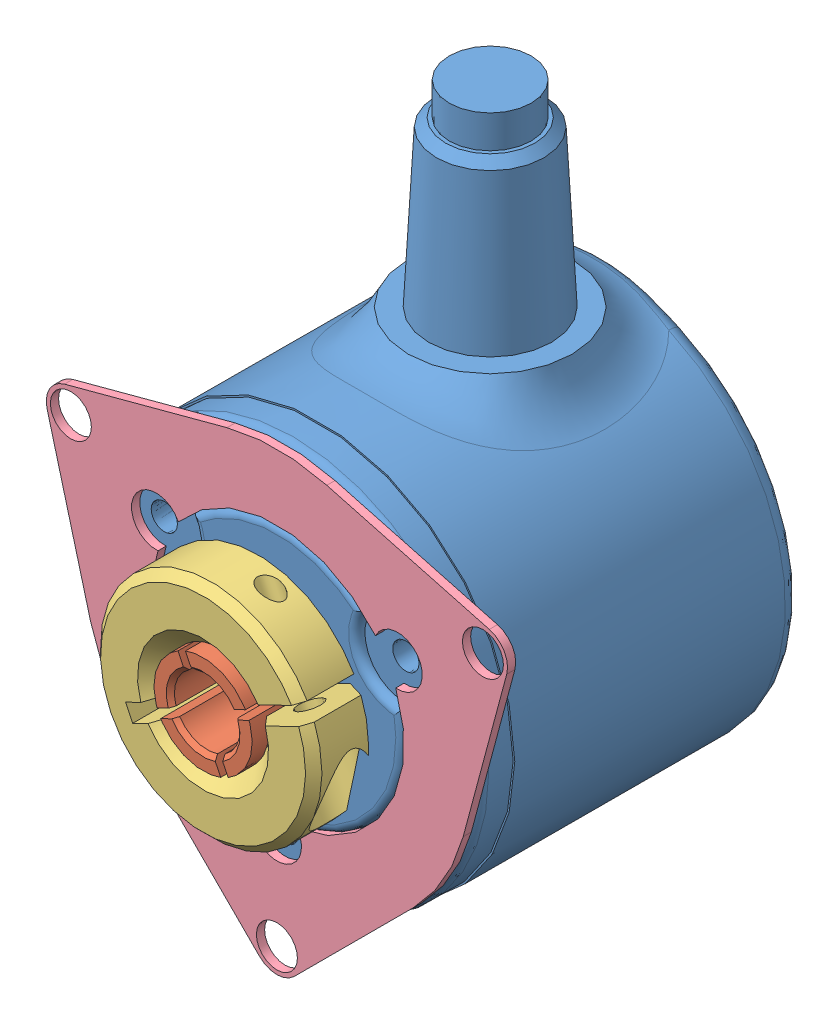
SolidWorks assembly Codeur_2MRH, configuration Default. Lengths in mm.
Overall size (38.09 42.8 24.5).
8 component instances, 6 part files, 16 mates.
Components (placement in the parent):
- corps_codeur_2MRH-1: corps_codeur_2MRH [Default] at (3.2886 -2.5929 -14.3048) size (24 36.75 20.04)
- mandrin_codeur_2MRH-1: mandrin_codeur_2MRH [Default] at (3.2886 -2.5929 -3.8048) x (-0.434638 0.900605 0) z (0 0 1) size (6 6 14)
- bague_codeur_2MRH-1: bague_codeur_2MRH [Default] at (3.2886 -2.5929 5.6952) x (0.434638 -0.900605 0) z (0 0 1) size (13.5 13.48 4.5)
- Socket Head Cap Screw_AM-2: Socket Head Cap Screw_AM [B18.3.1M - 1.6 x 0.35 x 5 Hex SHCS -- 5NHX] at (9.1066 -4.3376 7.9452) x (-0.434638 0.900605 0) z (0 0 1) (suppressed, hidden)
- Pan Slot Head_AM-4: Pan Slot Head_AM [B18.6.7M - M2 x 0.4 x 4 Slotted PHMS --4N] at (10.6498 1.6571 7.2952) x (0 0 -1) z (0.728333 -0.685223 0) (suppressed, hidden)
- Pan Slot Head_AM-5: Pan Slot Head_AM [B18.6.7M - M2 x 0.4 x 4 Slotted PHMS --4N] at (-4.0726 1.6571 7.2952) x (0 0 -1) z (0.998972 -0.045336 0) (suppressed, hidden)
- Pan Slot Head_AM-6: Pan Slot Head_AM [B18.6.7M - M2 x 0.4 x 4 Slotted PHMS --4N] at (3.2886 -11.0929 7.2952) x (0 0 -1) z (-0.043781 0.999041 0) (suppressed, hidden)
- Bride_membrane-1: Bride_membrane [Default] at (3.2886 -2.5929 5.6952) x (0.5 0.866025 0) z (-0.866025 0.5 0) size (28.11 0.5 27.75)
Mates (geometry in assembly coordinates):
- Coaxiale2: concentric anti-aligned: cylinder of corps_codeur_2MRH-1 through (3.2886 -2.5929 -3.8048) axis (0 0 1) radius 3; cylinder of mandrin_codeur_2MRH-1 through (3.2886 -2.5929 10.1952) axis (0 0 -1) radius 3
- Coïncidente1: coincident anti-aligned: plane of corps_codeur_2MRH-1 through (3.2886 -2.5929 -3.8048) normal (0 0 1); plane of mandrin_codeur_2MRH-1 through (3.2886 -2.5929 -3.8048) normal (0 0 -1)
- Coïncidente2: coincident anti-aligned: plane of corps_codeur_2MRH-1 through (3.2886 -2.5929 5.6952) normal (0 0 1); plane of bague_codeur_2MRH-1 through (3.2886 -2.5929 5.6952) normal (0 0 -1)
- Coaxiale3: concentric aligned: cylinder of mandrin_codeur_2MRH-1 through (3.2886 -2.5929 10.1952) axis (0 0 -1) radius 3; cylinder of bague_codeur_2MRH-1 through (3.2886 -2.5929 10.1952) axis (0 0 -1) radius 3
- Parallèle1: parallel aligned: plane of mandrin_codeur_2MRH-1 through (3.4051 -2.2591 0.1952) normal (0.434638 -0.900605 0); plane of bague_codeur_2MRH-1 through (9.1337 0.7831 5.6942) normal (0.434638 -0.900605 0)
- Coaxiale41: concentric anti-aligned: cylinder of bague_codeur_2MRH-1 through (8.4112 -2.8966 7.9452) axis (-0.434638 0.900605 0) radius 0.75; cylinder of Socket Head Cap Screw_AM-2 through (22.9064 -32.9318 7.9452) axis (0.434638 -0.900605 0) radius 1.5
- Coïncidente41: coincident anti-aligned: plane of bague_codeur_2MRH-1 through (8.4112 -2.8966 7.9452) normal (0.434638 -0.900605 0); plane of Socket Head Cap Screw_AM-2 through (7.0603 -3.5486 7.9452) normal (-0.434638 0.900605 0)
- Coaxiale81: concentric aligned: cylinder of corps_codeur_2MRH-1 through (10.6498 1.6571 5.1952) axis (0 0 1) radius 0.8; cylinder of Pan Slot Head_AM-4 through (10.6498 1.6571 32.6952) axis (0 0 1) radius 2
- Coaxiale91: concentric aligned: cylinder of corps_codeur_2MRH-1 through (-4.0726 1.6571 5.1952) axis (0 0 1) radius 0.8; cylinder of Pan Slot Head_AM-5 through (-4.0726 1.6571 32.6952) axis (0 0 1) radius 2
- Coaxiale101: concentric aligned: cylinder of corps_codeur_2MRH-1 through (3.2886 -11.0929 5.1952) axis (0 0 1) radius 0.8; cylinder of Pan Slot Head_AM-6 through (3.2886 -11.0929 32.6952) axis (0 0 1) radius 2
- Coïncidente102: coincident anti-aligned: plane of corps_codeur_2MRH-1 through (3.2886 -2.5929 5.1952) normal (0 0 1); plane of Bride_membrane-1 through (3.2886 -2.5929 5.1952) normal (0 0 -1)
- Coïncidente103: coincident aligned: circle of corps_codeur_2MRH-1; cylinder of Bride_membrane-1 through (3.2886 -2.5929 5.1952) axis (0 0 1) radius 7.75
- Coaxiale102: concentric aligned: cylinder of corps_codeur_2MRH-1 through (-4.0726 1.6571 5.1952) axis (0 0 1) radius 0.8; cylinder of Bride_membrane-1 through (-4.0726 1.6571 5.1952) axis (0 0 1) radius 1.5
- Coïncidente104: coincident anti-aligned: plane of Pan Slot Head_AM-5 through (-4.0273 2.6561 5.6952) normal (0 0 -1); plane of Bride_membrane-1 through (3.2886 -2.5929 5.6952) normal (0 0 1)
- Coïncidente105: coincident anti-aligned: plane of Pan Slot Head_AM-4 through (11.335 2.3854 5.6952) normal (0 0 -1); plane of Bride_membrane-1 through (3.2886 -2.5929 5.6952) normal (0 0 1)
- Coïncidente106: coincident anti-aligned: plane of Pan Slot Head_AM-6 through (2.2896 -11.1367 5.6952) normal (0 0 -1); plane of Bride_membrane-1 through (3.2886 -2.5929 5.6952) normal (0 0 1)
